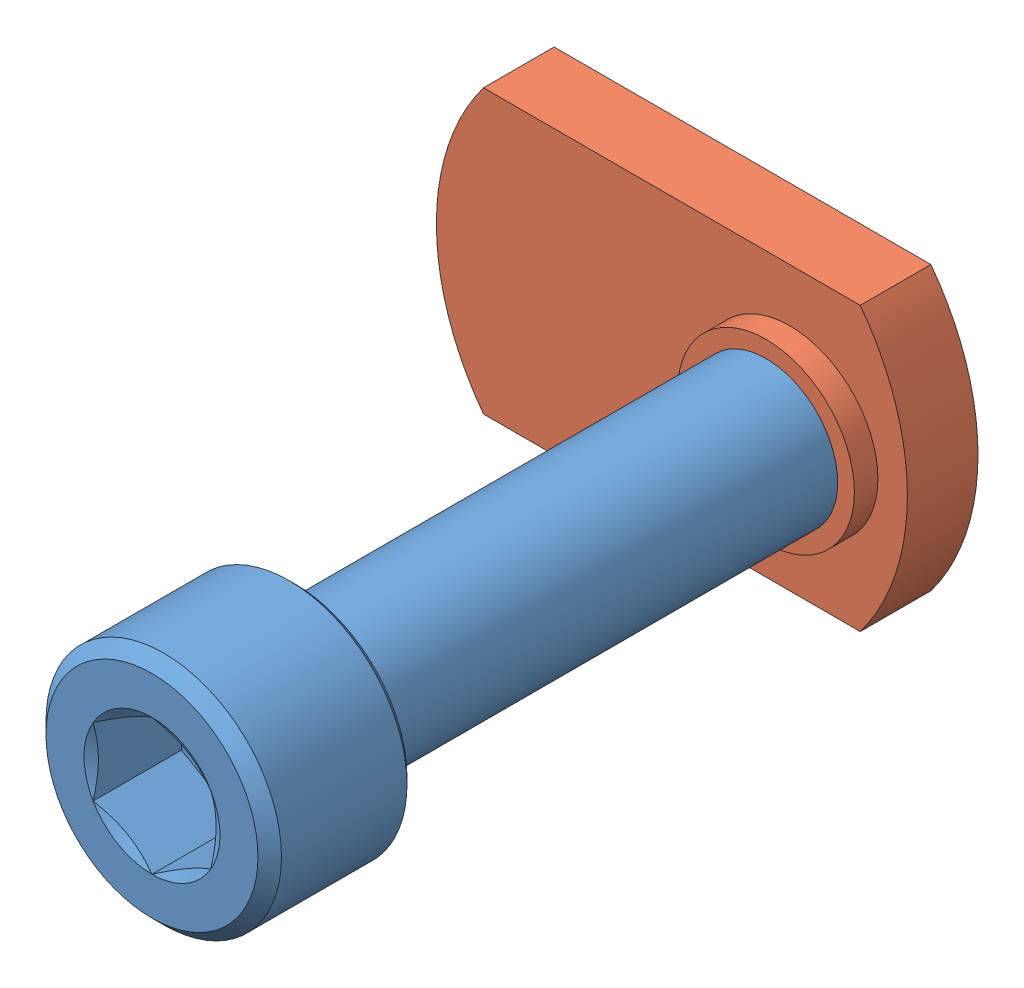
SolidWorks assembly Assem4, configuration Default. Lengths in mm.
Overall size (15.88 9.53 23.88).
2 component instances, 2 part files, 2 mates.
Components (placement in the parent):
- 10-32_x0.75_ SocketHead-1: 10-32_x0.75_ SocketHead [92196A269] at origin size (7.94 7.94 23.88)
- 10-32_T_Nut-1: 10-32_T_Nut [94581A128] at (-3.9688 0 -11.938) size (15.88 9.53 3.17)
Mates (geometry in assembly coordinates):
- Concentric1: concentric: cylinder of 10-32_x0.75_ SocketHead-1 through (0 0 -11.938) axis (0 0 -1) radius 2.413; cylinder of 10-32_T_Nut-1 through (0 0 -4.5277) axis (0 0 -1) radius 2.413
- Coincident1: coincident aligned: plane of 10-32_x0.75_ SocketHead-1 through (0 1.8177 -11.938) normal (0 0 -1); plane of 10-32_T_Nut-1 through (-3.9688 0 -6.909) normal (0 0 -1)
